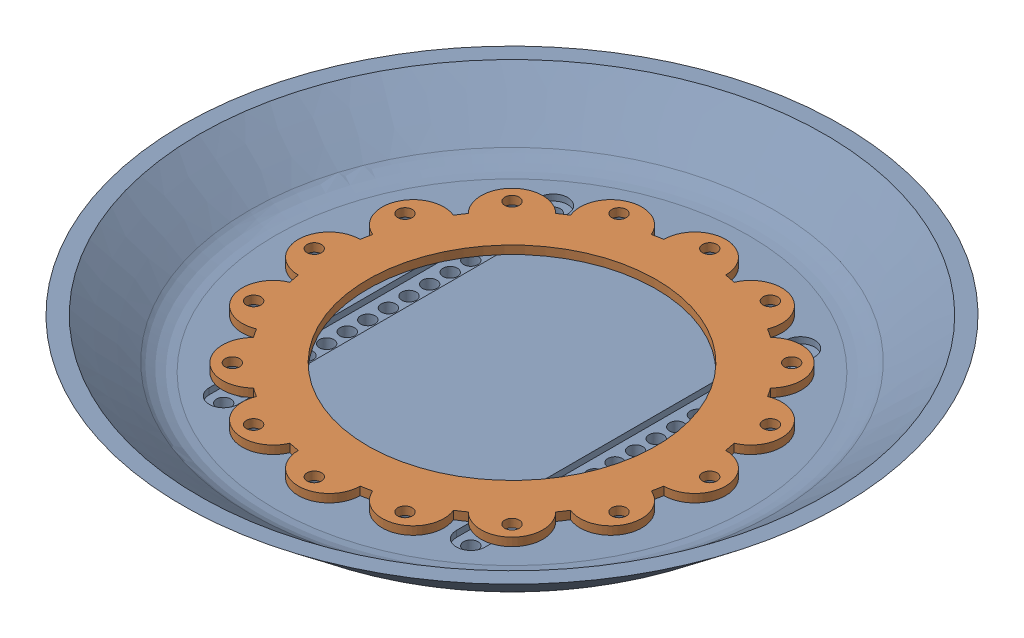
SolidWorks assembly Assem1, configuration Default. Lengths in mm.
Overall size (160 16 160).
2 component instances, 2 part files, 3 mates.
Components (placement in the parent):
- saghf-1: saghf [Default] at origin size (160 16 160)
- ayneh-1: ayneh [Default] at (0 6 0) x (-0.382683 0 0.92388) z (0 -1 0) size (103.74 103.74 2)
Mates (geometry in assembly coordinates):
- Coincident1: coincident anti-aligned: plane of saghf-1 through (-57.4902 4 0) normal (0 1 0); plane of ayneh-1 through (0 4 0) normal (0 -1 0)
- Concentric1: concentric aligned: circle of saghf-1; cylinder of ayneh-1 through (0 4 0) axis (0 1 0) radius 35
- Concentric2: concentric anti-aligned: cylinder of saghf-1 through (0 16 -48) axis (0 -1 0) radius 1.75; cylinder of ayneh-1 through (0 4 -48) axis (0 1 0) radius 1.75
